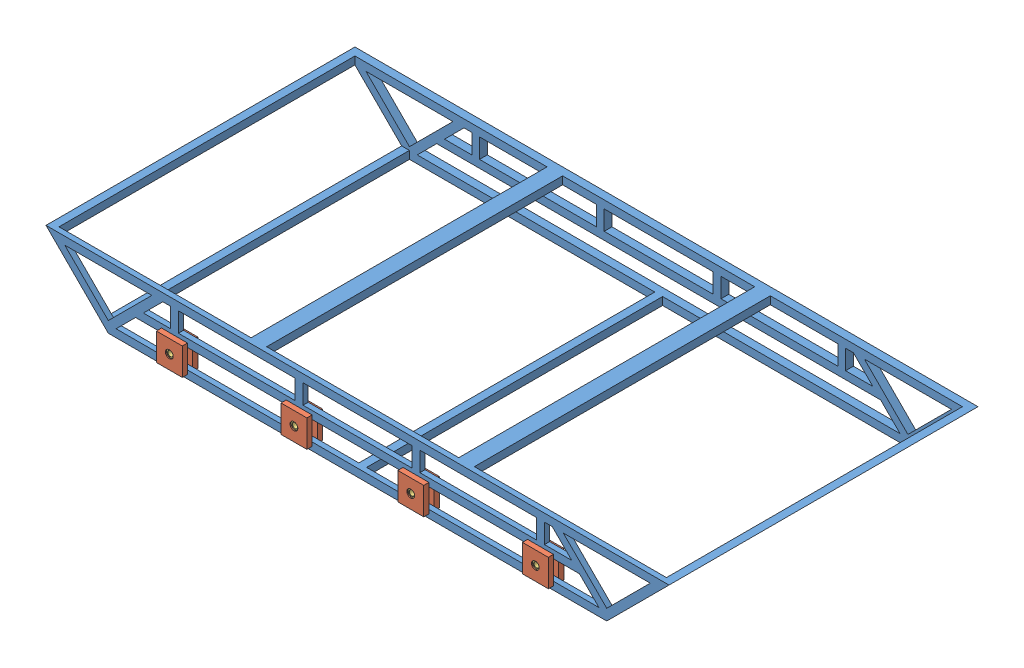
SolidWorks assembly Bodenwanne, configuration Standard. Lengths in mm.
Overall size (1200 120 605).
25 component instances, 3 part files, 28 mates.
Components (placement in the parent):
- Ramen Bodenwanne-1: Ramen Bodenwanne [Standard] at (-1765.5754 89.1394 1497.5) size (1200 120 595)
- Lagerklotz-1: Lagerklotz [Standard] at (-1453.8766 3.3198 1430) size (50 52.5 10)
  - Lagerklotz-1: Lagerklotz [Standard] at (-89.1989 -26.6804 47.5) size (50 52.5 10)
  - radial ball bearing_68_din-1: radial ball bearing_68_din [DIN 625 - 6000 - 8,DE,NC,8_68] at (-64.1989 -0.4304 53.5) x (0 0 -1) z (1 0 0) size (8 26 26)
- Lagerklotz-2: Lagerklotz [Standard] at (-1213.8766 3.3198 1430) size (50 52.5 10)
  - Lagerklotz-1: Lagerklotz [Standard] at (-89.1989 -26.6804 47.5) size (50 52.5 10)
  - radial ball bearing_68_din-1: radial ball bearing_68_din [DIN 625 - 6000 - 8,DE,NC,8_68] at (-64.1989 -0.4304 53.5) x (0 0 -1) z (1 0 0) size (8 26 26)
- Lagerklotz-3: Lagerklotz [Standard] at (-988.8766 3.3198 1430) size (50 52.5 10)
  - Lagerklotz-1: Lagerklotz [Standard] at (-89.1989 -26.6804 47.5) size (50 52.5 10)
  - radial ball bearing_68_din-1: radial ball bearing_68_din [DIN 625 - 6000 - 8,DE,NC,8_68] at (-64.1989 -0.4304 53.5) x (0 0 -1) z (1 0 0) size (8 26 26)
- Lagerklotz-4: Lagerklotz [Standard] at (-748.8766 3.3198 1430) size (50 52.5 10)
  - Lagerklotz-1: Lagerklotz [Standard] at (-89.1989 -26.6804 47.5) size (50 52.5 10)
  - radial ball bearing_68_din-1: radial ball bearing_68_din [DIN 625 - 6000 - 8,DE,NC,8_68] at (-64.1989 -0.4304 53.5) x (0 0 -1) z (1 0 0) size (8 26 26)
- Lagerklotz-5: Lagerklotz [Standard] at (-1582.2743 3.3198 1555) x (-1 0 0) z (0 0 -1) size (50 52.5 10)
  - Lagerklotz-1: Lagerklotz [Standard] at (-89.1989 -26.6804 47.5) size (50 52.5 10)
  - radial ball bearing_68_din-1: radial ball bearing_68_din [DIN 625 - 6000 - 8,DE,NC,8_68] at (-64.1989 -0.4304 53.5) x (0 0 -1) z (1 0 0) size (8 26 26)
- Lagerklotz-6: Lagerklotz [Standard] at (-1342.2743 3.3198 1555) x (-1 0 0) z (0 0 -1) size (50 52.5 10)
  - Lagerklotz-1: Lagerklotz [Standard] at (-89.1989 -26.6804 47.5) size (50 52.5 10)
  - radial ball bearing_68_din-1: radial ball bearing_68_din [DIN 625 - 6000 - 8,DE,NC,8_68] at (-64.1989 -0.4304 53.5) x (0 0 -1) z (1 0 0) size (8 26 26)
- Lagerklotz-7: Lagerklotz [Standard] at (-1117.2743 3.3198 1555) x (-1 0 0) z (0 0 -1) size (50 52.5 10)
  - Lagerklotz-1: Lagerklotz [Standard] at (-89.1989 -26.6804 47.5) size (50 52.5 10)
  - radial ball bearing_68_din-1: radial ball bearing_68_din [DIN 625 - 6000 - 8,DE,NC,8_68] at (-64.1989 -0.4304 53.5) x (0 0 -1) z (1 0 0) size (8 26 26)
- Lagerklotz-8: Lagerklotz [Standard] at (-877.2743 3.3198 1555) x (-1 0 0) z (0 0 -1) size (50 52.5 10)
  - Lagerklotz-1: Lagerklotz [Standard] at (-89.1989 -26.6804 47.5) size (50 52.5 10)
  - radial ball bearing_68_din-1: radial ball bearing_68_din [DIN 625 - 6000 - 8,DE,NC,8_68] at (-64.1989 -0.4304 53.5) x (0 0 -1) z (1 0 0) size (8 26 26)
Mates (geometry in assembly coordinates):
- Deckungsgleich1: coincident anti-aligned: plane of Ramen Bodenwanne-1 through (-1765.5754 89.1394 1487.5) normal (0 0 -1); plane of Lagerklotz-1/Lagerklotz-1 through (-1543.0754 -23.3606 1487.5) normal (0 0 1)
- Deckungsgleich2: coincident anti-aligned: plane of Ramen Bodenwanne-1 through (-1765.5754 89.1394 1487.5) normal (0 0 -1); plane of Lagerklotz-2/Lagerklotz-1 through (-1303.0754 -23.3606 1487.5) normal (0 0 1)
- Deckungsgleich3: coincident anti-aligned: plane of Ramen Bodenwanne-1 through (-1765.5754 89.1394 1487.5) normal (0 0 -1); plane of Lagerklotz-3/Lagerklotz-1 through (-1078.0754 -23.3606 1487.5) normal (0 0 1)
- Deckungsgleich4: coincident anti-aligned: plane of Ramen Bodenwanne-1 through (-1765.5754 89.1394 1487.5) normal (0 0 -1); plane of Lagerklotz-4/Lagerklotz-1 through (-838.0754 -23.3606 1487.5) normal (0 0 1)
- Deckungsgleich5: coincident anti-aligned: plane of Ramen Bodenwanne-1 through (-1765.5754 89.1394 1497.5) normal (0 0 1); plane of Lagerklotz-8/Lagerklotz-1 through (-788.0754 -23.3606 1497.5) normal (0 0 -1)
- Deckungsgleich6: coincident anti-aligned: plane of Ramen Bodenwanne-1 through (-1765.5754 89.1394 1497.5) normal (0 0 1); plane of Lagerklotz-7/Lagerklotz-1 through (-1028.0754 -23.3606 1497.5) normal (0 0 -1)
- Deckungsgleich7: coincident anti-aligned: plane of Ramen Bodenwanne-1 through (-1765.5754 89.1394 1497.5) normal (0 0 1); plane of Lagerklotz-6/Lagerklotz-1 through (-1253.0754 -23.3606 1497.5) normal (0 0 -1)
- Deckungsgleich8: coincident anti-aligned: plane of Ramen Bodenwanne-1 through (-1765.5754 89.1394 1497.5) normal (0 0 1); plane of Lagerklotz-5/Lagerklotz-1 through (-1493.0754 -23.3606 1497.5) normal (0 0 -1)
- Parallel1: parallel aligned: line of Ramen Bodenwanne-1 through (-1765.5754 89.1394 1497.5) axis (1 0 0); line of Lagerklotz-5/Lagerklotz-1 through (-1543.0754 29.1394 1507.5) axis (1 0 0)
- Parallel2: parallel aligned: line of Ramen Bodenwanne-1 through (-1765.5754 89.1394 1497.5) axis (1 0 0); line of Lagerklotz-6/Lagerklotz-1 through (-1303.0754 29.1394 1507.5) axis (1 0 0)
- Parallel3: parallel aligned: line of Ramen Bodenwanne-1 through (-1765.5754 89.1394 1497.5) axis (1 0 0); line of Lagerklotz-7/Lagerklotz-1 through (-1078.0754 29.1394 1507.5) axis (1 0 0)
- Parallel4: parallel aligned: line of Ramen Bodenwanne-1 through (-1765.5754 89.1394 1497.5) axis (1 0 0); line of Lagerklotz-8/Lagerklotz-1 through (-838.0754 29.1394 1507.5) axis (1 0 0)
- Abstand1: distance = 7.5 mm: line of Lagerklotz-5/Lagerklotz-1 through (-1543.0754 29.1394 1497.5) axis (1 0 0); line of Ramen Bodenwanne-1 through (-1510.5754 36.6394 1497.5) axis (1 0 0)
- Abstand2: distance = 7.5 mm: line of Lagerklotz-6/Lagerklotz-1 through (-1303.0754 29.1394 1497.5) axis (1 0 0); line of Ramen Bodenwanne-1 through (-1270.5754 36.6394 1497.5) axis (1 0 0)
- Abstand3: distance = 7.5 mm: line of Lagerklotz-7/Lagerklotz-1 through (-1078.0754 29.1394 1497.5) axis (1 0 0); line of Ramen Bodenwanne-1 through (-1045.5754 36.6394 1497.5) axis (1 0 0)
- Abstand4: distance = 7.5 mm: line of Lagerklotz-8/Lagerklotz-1 through (-838.0754 29.1394 1497.5) axis (1 0 0); line of Ramen Bodenwanne-1 through (-805.5754 36.6394 1497.5) axis (1 0 0)
- Abstand5: distance = 7.5 mm: line of Lagerklotz-4/Lagerklotz-1 through (-788.0754 29.1394 1487.5) axis (-1 0 0); line of Ramen Bodenwanne-1 through (-1045.5754 36.6394 1487.5) axis (1 0 0)
- Abstand6: distance = 7.5 mm: line of Lagerklotz-3/Lagerklotz-1 through (-1028.0754 29.1394 1487.5) axis (-1 0 0); line of Ramen Bodenwanne-1 through (-1270.5754 36.6394 1487.5) axis (1 0 0)
- Abstand7: distance = 7.5 mm: line of Lagerklotz-2/Lagerklotz-1 through (-1253.0754 29.1394 1487.5) axis (-1 0 0); line of Ramen Bodenwanne-1 through (-1510.5754 36.6394 1487.5) axis (1 0 0)
- Abstand8: distance = 7.5 mm: line of Lagerklotz-1/Lagerklotz-1 through (-1493.0754 29.1394 1487.5) axis (-1 0 0); line of Ramen Bodenwanne-1 through (-1578.0754 36.6394 1487.5) axis (1 0 0)
- Abstand10: distance = 222.5 mm: line of Lagerklotz-5/Lagerklotz-1 through (-1543.0754 -23.3606 1497.5) axis (0 1 0); point of Ramen Bodenwanne-1
- Abstand11: distance = 462.5 mm: line of Lagerklotz-6/Lagerklotz-1 through (-1303.0754 -23.3606 1497.5) axis (0 1 0); unknown of Ramen Bodenwanne-1
- Abstand12: distance = 462.5 mm: line of Lagerklotz-7/Lagerklotz-1 through (-1028.0754 29.1394 1497.5) axis (0 -1 0); unknown of Ramen Bodenwanne-1
- Abstand13: distance = 222.5 mm: line of Lagerklotz-8/Lagerklotz-1 through (-788.0754 29.1394 1497.5) axis (0 -1 0); unknown of Ramen Bodenwanne-1
- Deckungsgleich27: coincident aligned: plane of Lagerklotz-4/Lagerklotz-1 through (-788.0754 29.1394 1487.5) normal (1 0 0); plane of Lagerklotz-8/Lagerklotz-1 through (-788.0754 29.1394 1497.5) normal (1 0 0)
- Deckungsgleich28: coincident aligned: plane of Lagerklotz-3/Lagerklotz-1 through (-1028.0754 29.1394 1487.5) normal (1 0 0); plane of Lagerklotz-7/Lagerklotz-1 through (-1028.0754 29.1394 1497.5) normal (1 0 0)
- Deckungsgleich29: coincident aligned: plane of Lagerklotz-2/Lagerklotz-1 through (-1253.0754 29.1394 1487.5) normal (1 0 0); plane of Lagerklotz-6/Lagerklotz-1 through (-1253.0754 29.1394 1497.5) normal (1 0 0)
- Deckungsgleich30: coincident aligned: plane of Lagerklotz-1/Lagerklotz-1 through (-1493.0754 29.1394 1487.5) normal (1 0 0); plane of Lagerklotz-5/Lagerklotz-1 through (-1493.0754 29.1394 1497.5) normal (1 0 0)
